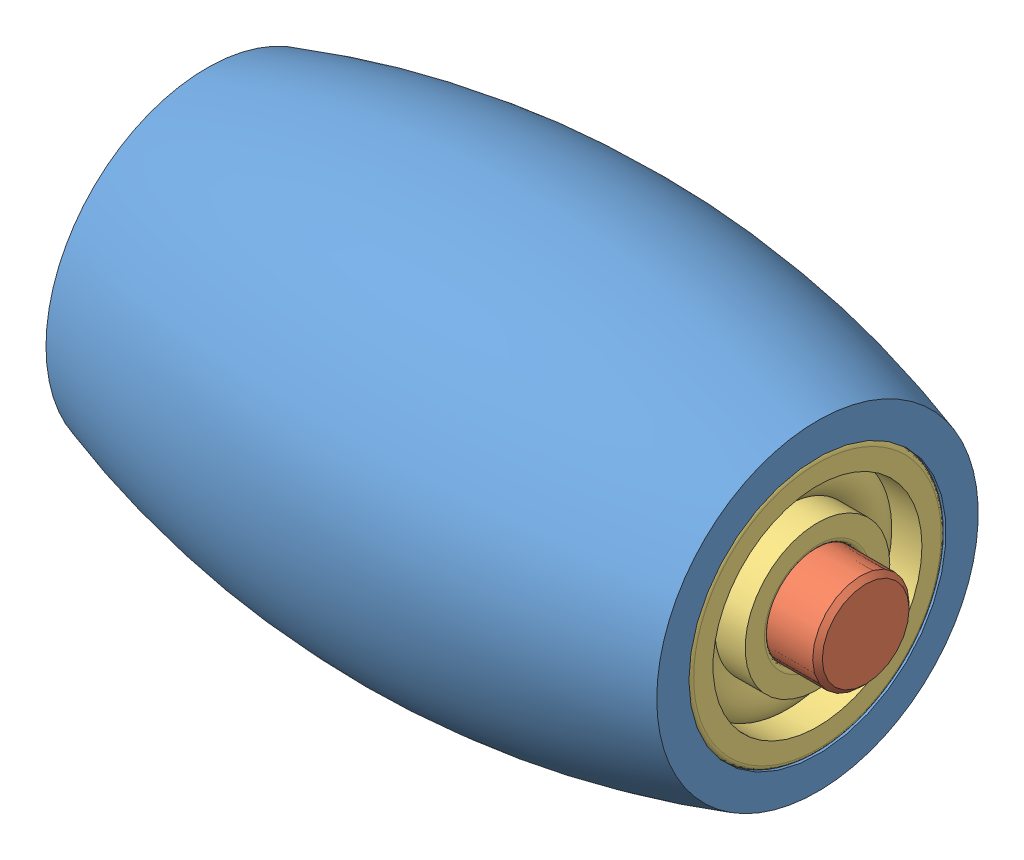
SolidWorks assembly Roller assenbly, configuration Default. Lengths in mm.
Overall size (22 13 13).
4 component instances, 3 part files, 6 mates.
Components (placement in the parent):
- Roller-1: Roller [Default] at origin size (19 13 13)
- Pin-1: Pin [Default] at (9.5 0 0) x (0 -0.246767 -0.969075) z (1 0 0) size (3 3 22)
- instrument ball bearing_68_am-1: instrument ball bearing_68_am [AFBMA 12.1.4.1 - 0030-8 - 8,SI,NC,8_68] at (17.5 0 0) size (3 8 8)
- instrument ball bearing_68_am-2: instrument ball bearing_68_am [AFBMA 12.1.4.1 - 0030-8 - 8,SI,NC,8_68] at (1.5 0 0) x (-1 0 0) z (0 -0.924225 -0.381849) size (3 8 8)
Mates (geometry in assembly coordinates):
- Concentric1: concentric aligned: cylinder of Roller-1 through (0 0 0) axis (-1 0 0) radius 2; cylinder of Pin-1 through (20.5 0 0) axis (-1 0 0) radius 1.5
- Width1: width anti-aligned: plane of Pin-1 through (20.5 0 0) normal (1 0 0); plane of Roller-1 through (-1.5 0 0) normal (-1 0 0); plane of Pin-1 through (0 4 0) normal (-1 0 0); plane of Roller-1 through (19 4 0) normal (1 0 0)
- Concentric2: concentric anti-aligned: cylinder of Roller-1 through (0 0 0) axis (-1 0 0) radius 4; cylinder of instrument ball bearing_68_am-1 through (-3.1375 0 0) axis (1 0 0) radius 4
- Coincident1: coincident aligned: plane of Roller-1 through (19 4 0) normal (1 0 0); plane of instrument ball bearing_68_am-1 through (19 3.85 0) normal (1 0 0)
- Concentric3: concentric aligned: cylinder of Roller-1 through (0 0 0) axis (-1 0 0) radius 4; cylinder of instrument ball bearing_68_am-2 through (22.1375 0 0) axis (-1 0 0) radius 4
- Coincident2: coincident aligned: plane of Roller-1 through (0 4 0) normal (-1 0 0); plane of instrument ball bearing_68_am-2 through (0 1.4701 -3.5583) normal (-1 0 0)
